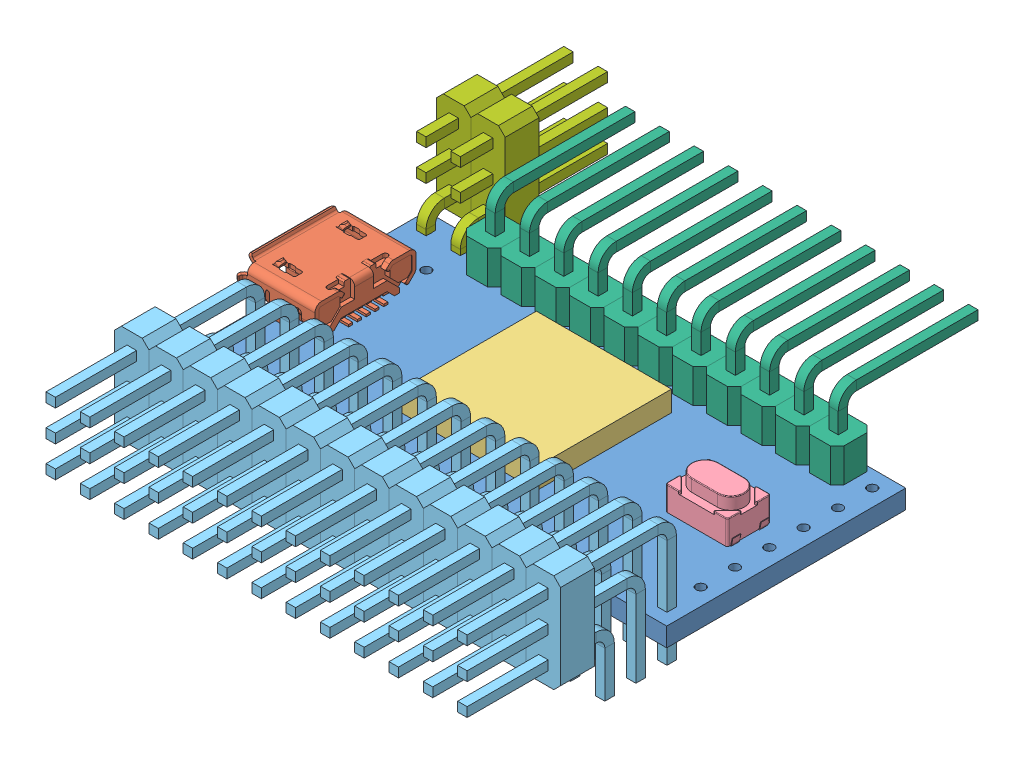
SolidWorks assembly Teensy_4.0_Assembly, configuration Default. Lengths in mm.
Overall size (36.8 10.75 40.92).
7 component instances, 7 part files, 19 mates.
Components (placement in the parent):
- Teensy_4.0_PCB-1: Teensy_4.0_PCB [Default] at (-32.9666 11.0804 9.3926) size (35.5 1.4 17.7)
- Micro USB-B Female 5Pin SMD-1: Micro USB-B Female 5Pin SMD [Default] at (-46.3666 13.7054 9.3926) x (0 0 1) z (0 1 0) size (8.05 5.8 3.73)
- NXP iMXRT1062-1: NXP iMXRT1062 [Default] at (-33.7166 12.4804 9.3926) x (0 0 1) z (-1 0 0) size (10 1.52 10)
- SKRPACE010 v4-1: SKRPACE010 v4 [Default] at (-22.5666 12.5304 7.7926) size (4.89 2.55 3.2)
- 13x triple angled pin header-1: 13x triple angled pin header [Default] at (-48.1866 12.1304 26.1526) x (1 0 0) z (0 1 0) size (33.02 15.5 10.35)
- 11x angled pin header-1: 11x angled pin header [Default] at (-20.2466 12.4804 0.4326) size (27.94 8.35 11.35)
- 2x cut triple angled pin header-1: 2x cut triple angled pin header [Default] at (-45.6866 12.5304 -2.7674) x (-1 0 0) z (0 1 0) size (5.08 15.15 10.35)
Mates (geometry in assembly coordinates):
- Coincident1: coincident anti-aligned: plane of Teensy_4.0_PCB-1 through (-32.9666 12.4804 9.3926) normal (0 1 0); plane of Micro USB-B Female 5Pin SMD-1 through (-51.3666 12.4804 6.7755) normal (0 -1 0)
- Parallel1: parallel aligned: plane of Micro USB-B Female 5Pin SMD-1 through (-46.4666 14.6304 10.0926) normal (1 0 0)
- Coincident3: coincident aligned: plane of Teensy_4.0_PCB-1 through (-32.9666 11.0804 9.3926) normal (0 0 1); plane of Micro USB-B Female 5Pin SMD-1 through (-46.3666 13.7054 9.3926) normal (0 0 1)
- Distance1: distance = 1 mm aligned: plane of Micro USB-B Female 5Pin SMD-1 through (-49.7166 13.9804 5.3926) normal (-1 0 0); plane of Teensy_4.0_PCB-1 through (-50.7166 12.4804 0.5426) normal (-1 0 0)
- Coincident5: coincident anti-aligned: plane of Teensy_4.0_PCB-1 through (-32.9666 12.4804 9.3926) normal (0 1 0); plane of NXP iMXRT1062-1 through (-33.7166 12.4804 9.3926) normal (0 -1 0)
- Distance2: distance = 13.5 mm aligned: plane of NXP iMXRT1062-1 through (-28.7166 14.0004 4.3926) normal (1 0 0); plane of Teensy_4.0_PCB-1 through (-15.2166 12.4804 0.5426) normal (1 0 0)
- Coincident7: coincident aligned: plane of Teensy_4.0_PCB-1 through (-32.9666 11.0804 9.3926) normal (0 0 1); plane of NXP iMXRT1062-1 through (-33.7166 12.4804 9.3926) normal (0 0 1)
- Coincident8: coincident anti-aligned: plane of Teensy_4.0_PCB-1 through (-32.9666 12.4804 9.3926) normal (0 1 0); plane of SKRPACE010 v4-1 through (-18.2666 12.4804 8.3426) normal (0 -1 0)
- Coincident10: coincident aligned: plane of Teensy_4.0_PCB-1 through (-32.9666 11.0804 9.3926) normal (0 0 1); plane of SKRPACE010 v4-1 through (-22.5666 12.5304 9.3926) normal (0 0 1)
- Distance3: distance = 2.75 mm aligned: plane of Teensy_4.0_PCB-1 through (-15.2166 12.4804 0.5426) normal (1 0 0); plane of SKRPACE010 v4-1 through (-17.9666 12.5304 10.9926) normal (1 0 0)
- Concentric1: concentric aligned: line of Angled pin header-1 through (-46.9366 17.0804 17.0026) axis (0 -1 0); cylinder of Teensy_4.0_PCB-1 through (-46.9366 12.4804 17.0026) axis (0 -1 0) radius 0.35
- Distance4: distance = 2 mm aligned: plane of Teensy_4.0_PCB-1 through (-32.9666 11.0804 9.3926) normal (0 -1 0); plane of Angled pin header-1 through (-48.1866 9.0804 22.9526) normal (0 -1 0)
- Parallel2: parallel aligned: line of Teensy_4.0_PCB-1 through (-50.7166 11.0804 18.2426) axis (1 0 0); line of Angled pin header-1 through (-27.3666 12.1304 23.6526) axis (1 0 0)
- Concentric2: concentric aligned: cylinder of Teensy_4.0_PCB-1 through (-18.9966 12.4804 1.7826) axis (0 -1 0) radius 0.35; line of 11x angled pin header-1 through (-18.9966 16.4804 1.7826) axis (0 -1 0)
- Coincident11: coincident anti-aligned: plane of Teensy_4.0_PCB-1 through (-32.9666 12.4804 9.3926) normal (0 1 0); plane of 11x angled pin header-1 through (-25.3266 12.4804 0.4326) normal (0 -1 0)
- Parallel3: parallel aligned: plane of Teensy_4.0_PCB-1 through (-50.7166 12.4804 0.5426) normal (0 0 -1); plane of 11x angled pin header-1 through (-20.2466 14.9804 0.4326) normal (0 0 -1)
- Concentric3: concentric aligned: line of 2x cut triple angled pin header-1 through (-46.9366 12.8804 1.7826) axis (0 -1 0); cylinder of Teensy_4.0_PCB-1 through (-46.9366 12.4804 1.7826) axis (0 -1 0) radius 0.35
- Parallel4: parallel aligned: plane of Teensy_4.0_PCB-1 through (-50.7166 12.4804 0.5426) normal (0 0 -1); plane of 2x cut triple angled pin header-1 through (-45.6866 12.5304 -2.7674) normal (0 0 -1)
- Coincident12: coincident aligned: plane of 11x angled pin header-1 through (-45.6466 9.4804 0.4326) normal (0 -1 0); plane of 2x cut triple angled pin header-1 through (-48.2266 9.4804 0.4326) normal (0 -1 0)
